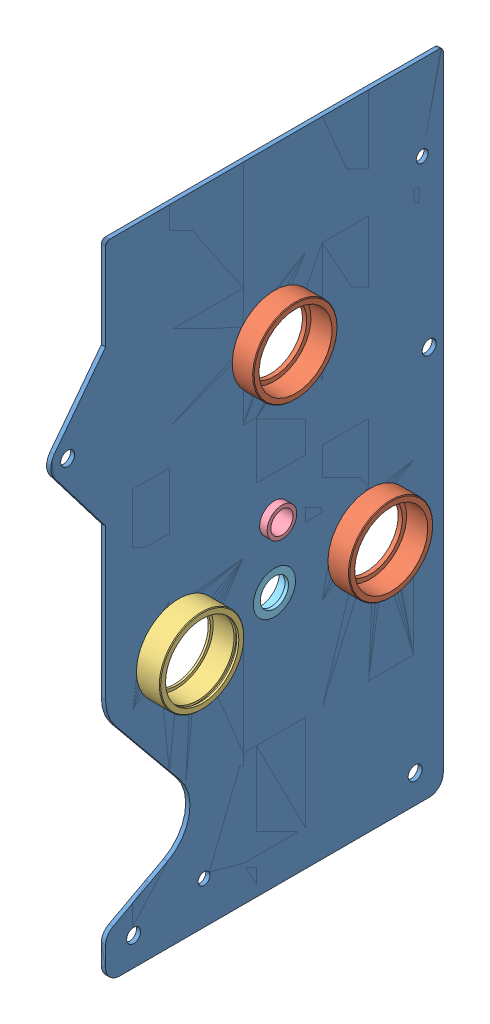
SolidWorks assembly ТП.002.01.01.01.00 - Щека редуктора левая, configuration 00. Lengths in mm.
Overall size (28.05 457 278.9).
6 component instances, 5 part files, 11 mates.
Components (placement in the parent):
- ТП.002.01.01.01.01 - Щека редуктора - 3мм (2 шт)-1: ТП.002.01.01.01.01 - Щека редуктора - 3мм (2 шт) [По умолчанию] at origin size (3 457 278.9)
- ТП.002.01.01.01.02 - Обойма 52 h-15мм без стопора (3мм)-4: ТП.002.01.01.01.02 - Обойма 52 h-15мм без стопора (3мм) [00] at (-98.05 0 0) x (-1 0 0) z (0 -0.924225 -0.381849) size (18 60 60)
- ТП.002.01.01.01.02(01) - Обойма 52 h-15мм со стопором (3мм)-6: ТП.002.01.01.01.02(01) - Обойма 52 h-15мм со стопором (3мм) [00] at (0 -155.8076 68) x (-1 0 0) z (0 -0.924225 -0.381849) size (19.7 60 60)
- ТП.002.01.01.01.02 - Обойма 52 h-15мм без стопора (3мм)-5: ТП.002.01.01.01.02 - Обойма 52 h-15мм без стопора (3мм) [00] at (-98.05 -155.8076 -68) x (-1 0 0) z (0 -0.924225 -0.381849) size (18 60 60)
- ТП.002.01.01.01.03 - Втулка перекидушки-1: ТП.002.01.01.01.03 - Втулка перекидушки [00] at (-98.05 -67.9966 -101.6647) x (-1 0 0) z (0 -0.924225 -0.381849) size (16.7 24 24)
- ТП.002.01.01.01.04 - ОБОЙМА 28-1: ТП.002.01.01.01.04 - ОБОЙМА 28 [По умолчанию] at (-7.5 -156 0) x (-1 0 0) z (0 -0.924225 -0.381849) size (10.5 33 33)
Mates (geometry in assembly coordinates):
- Совпадение78: coincident: plane of ТП.002.01.01.01.04 - ОБОЙМА 28-1 through (0 -150.2723 -13.8634) normal (1 0 0); plane of ТП.002.01.01.01.01 - Щека редуктора - 3мм (2 шт)-1 through (0 0 0) normal (-1 0 0)
- Концентричный177: concentric: cylinder of ТП.002.01.01.01.04 - ОБОЙМА 28-1 through (-7.5 -156 0) axis (-1 0 0) radius 15; cylinder of ТП.002.01.01.01.01 - Щека редуктора - 3мм (2 шт)-1 through (0 -156 0) axis (1 0 0) radius 15
- Концентричный178: concentric: cylinder of ТП.002.01.01.01.01 - Щека редуктора - 3мм (2 шт)-1 through (0 0 0) axis (1 0 0) radius 29; cylinder of ТП.002.01.01.01.02 - Обойма 52 h-15мм без стопора (3мм)-4 through (10.5 0 0) axis (-1 0 0) radius 29
- Совпадение80: coincident: plane of ТП.002.01.01.01.01 - Щека редуктора - 3мм (2 шт)-1 through (3 0 0) normal (1 0 0); plane of ТП.002.01.01.01.02 - Обойма 52 h-15мм без стопора (3мм)-4 through (3 11.4555 -27.7267) normal (-1 0 0)
- Концентричный179: concentric: cylinder of ТП.002.01.01.01.01 - Щека редуктора - 3мм (2 шт)-1 through (0 -155.8076 -68) axis (1 0 0) radius 29; cylinder of ТП.002.01.01.01.02 - Обойма 52 h-15мм без стопора (3мм)-5 through (10.5 -155.8076 -68) axis (-1 0 0) radius 29
- Концентричный180: concentric: cylinder of ТП.002.01.01.01.01 - Щека редуктора - 3мм (2 шт)-1 through (0 -155.8076 68) axis (1 0 0) radius 29; cylinder of ТП.002.01.01.01.02(01) - Обойма 52 h-15мм со стопором (3мм)-6 through (1000 -155.8076 68) axis (-1 0 0) radius 29
- Совпадение81: coincident: plane of ТП.002.01.01.01.01 - Щека редуктора - 3мм (2 шт)-1 through (3 0 0) normal (1 0 0); plane of ТП.002.01.01.01.02 - Обойма 52 h-15мм без стопора (3мм)-5 through (3 -144.3521 -95.7267) normal (-1 0 0)
- Совпадение82: coincident: plane of ТП.002.01.01.01.01 - Щека редуктора - 3мм (2 шт)-1 through (3 0 0) normal (1 0 0); plane of ТП.002.01.01.01.02(01) - Обойма 52 h-15мм со стопором (3мм)-6 through (3 -144.3521 40.2733) normal (-1 0 0)
- Концентричный181: concentric: cylinder of ТП.002.01.01.01.01 - Щека редуктора - 3мм (2 шт)-1 through (0 -110 0) axis (1 0 0) radius 10.5; cylinder of ТП.002.01.01.01.03 - Втулка перекидушки-1 through (8.7019 -110 0) axis (1 0 0) radius 10.5
- Совпадение83: coincident: plane of ТП.002.01.01.01.01 - Щека редуктора - 3мм (2 шт)-1 through (0 0 0) normal (-1 0 0); plane of ТП.002.01.01.01.03 - Втулка перекидушки-1 through (0 -105.9906 -9.7044) normal (1 0 0)
- Совпадение84: coordinate: point of ТП.002.01.01.01.01 - Щека редуктора - 3мм (2 шт)-1; point of assembly
